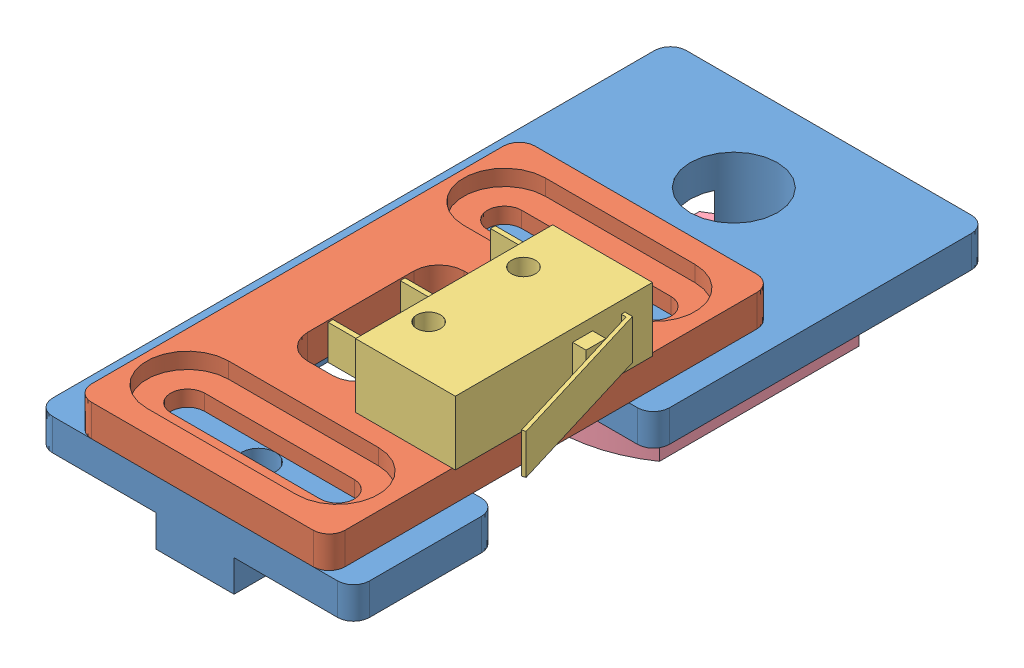
SolidWorks assembly Frame Carriage Endstop Assembly LH, configuration Default. Lengths in mm.
Overall size (35 22.28 63.5).
5 component instances, 5 part files, 15 mates.
Components (placement in the parent):
- Carriage Axis Endstop Mount Base LH-1: Carriage Axis Endstop Mount Base LH [Default] at (1.0367 29.7611 11.3307) size (31.75 6.35 63.5)
- Carriage Axis Endstop Mount Slide LH-1: Carriage Axis Endstop Mount Slide LH [Default] at (4.9348 32.9361 74.8307) size (25.4 3.17 44.45)
- Endstop-1: Endstop [Default] at (20.6348 42.5111 62.4807) x (0 0 -1) z (-1 0 0) size (19.75 6.4 19.65)
- 5_16in T-Slot Nut-3: 5_16in T-Slot Nut [Default] at (8.9117 20.9061 16.3057) x (0 0 1) z (-1 0 0) size (25 5.68 16)
- 5_16in x 0.5in T-Slot Bolt-1: 5_16in x 0.5in T-Slot Bolt [Default] at (16.9117 20.2361 20.8557) x (0 0 -1) z (1 0 0) size (16.95 16.6 16.95)
Mates (geometry in assembly coordinates):
- Coincident1: coincident: plane of Carriage Axis Endstop Mount Base LH-1 through (1.0367 32.9361 74.8307) normal (0 1 0); plane of Carriage Axis Endstop Mount Slide LH-1 through (4.9348 32.9361 74.8307) normal (0 -1 0)
- Coincident2: coincident: plane of Carriage Axis Endstop Mount Base LH-1 through (1.0367 29.7611 74.8307) normal (0 0 1); plane of Carriage Axis Endstop Mount Slide LH-1 through (4.9348 36.1111 74.8307) normal (0 0 1)
- Coincident3: coincident: plane of Carriage Axis Endstop Mount Slide LH-1 through (4.9348 36.1111 74.8307) normal (0 1 0); plane of Endstop-1 through (20.6348 36.1111 62.4807) normal (0 -1 0)
- Concentric1: concentric: cylinder of Carriage Axis Endstop Mount Slide LH-1 through (22.8348 36.1111 57.3557) axis (0 -1 0) radius 1.2; cylinder of Endstop-1 through (22.8348 36.1111 57.3557) axis (0 1 0) radius 1.2
- Concentric2: concentric: cylinder of Carriage Axis Endstop Mount Base LH-1 through (16.9117 26.5861 20.8557) axis (0 1 0) radius 4.3656; cylinder of ? through (16.9117 32.9361 20.8557) axis (0 -1 0) radius 3.9688
- Coincident4: coincident: plane of Carriage Axis Endstop Mount Base LH-1 through (1.0367 32.9361 74.8307) normal (0 1 0); plane of ? through (16.9117 32.9361 20.8557) normal (0 -1 0)
- Concentric3: concentric: cylinder of ? through (16.9117 32.9361 20.8557) axis (0 -1 0) radius 3.9688; cylinder of 5_16in T-Slot Nut-3 through (16.9117 24.5861 20.8557) axis (0 -1 0) radius 3.9688
- Parallel1: parallel: plane of Carriage Axis Endstop Mount Base LH-1 through (1.0367 29.7611 74.8307) normal (-1 0 0); plane of 5_16in T-Slot Nut-3 through (24.9117 24.5861 16.3057) normal (1 0 0)
- Coincident8: coincident: plane of Carriage Axis Endstop Mount Base LH-1 through (1.0367 26.5861 74.8307) normal (0 -1 0); plane of ? through (16.9117 26.5861 27.8557) normal (0 1 0)
- Concentric4: concentric: cylinder of ? through (16.9117 32.9361 20.8557) axis (0 -1 0) radius 3.9688; cylinder of ? through (16.9117 22.9061 20.8557) axis (0 1 0) radius 3.9688
- Parallel2: parallel: plane of Carriage Axis Endstop Mount Base LH-1 through (1.0367 29.7611 74.8307) normal (-1 0 0); plane of ? through (8.9117 22.9061 16.3057) normal (-1 0 0)
- Concentric5: concentric: circle of Carriage Axis Endstop Mount Base LH-1; cylinder of 5_16in x 0.5in T-Slot Bolt-1 through (16.9117 32.9361 20.8557) axis (0 -1 0) radius 3.9688
- Concentric6: concentric: circle of Carriage Axis Endstop Mount Base LH-1; circle of 5_16in T-Slot Nut-3
- Coincident10: coincident: plane of Carriage Axis Endstop Mount Base LH-1 through (1.0367 32.9361 74.8307) normal (0 1 0); circle of 5_16in x 0.5in T-Slot Bolt-1
- Coincident12: coincident: plane of Carriage Axis Endstop Mount Base LH-1 through (1.0367 26.5861 74.8307) normal (0 -1 0); plane of 5_16in T-Slot Nut-3 through (16.9117 26.5861 20.8557) normal (0 1 0)
